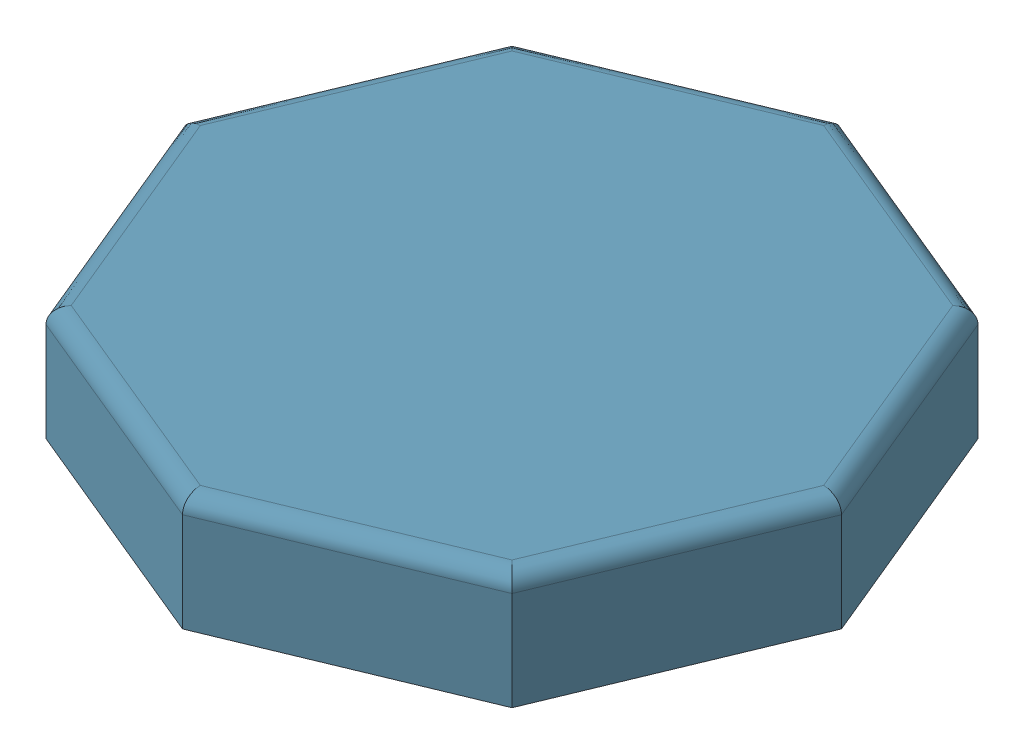
SolidWorks assembly SPYDER_VER_2, configuration Default. Lengths in mm.
Overall size (399.81 90 399.81).
100 component instances, 39 part files, 25 mates.
Components (placement in the parent):
- SP-chassis-1: SP-chassis [Default] at (163.298 278.0074 409.538) x (-1 0 0) z (0 -1 0) size (391.97 371.45 23)
- PIXHWAK PX4 2.8-1: PIXHWAK PX4 2.8 [Default] at (163.298 278.0074 533.5224) size (44.1 12.1 85)
- PIXHAWK_MOUNTS_1-1: PIXHAWK_MOUNTS_1 [Default] at (170.0442 283.0074 574.7577) x (0 0 -1) z (0 -1 0) size (15 50 5)
- PIXHAWK_MOUNTS_1-2: PIXHAWK_MOUNTS_1 [Default] at (169.4157 278.0074 492.2871) x (0 0 1) z (0 1 0) size (15 50 5)
- RasPI-4.iges-1: RasPI-4.iges [Default] at (242.8847 278.0074 515.731) x (-0.92388 0 0.382683) z (-0.382683 0 -0.92388) size (70 53.6 99)
  - Top v2.iges-1: Top v2.iges [Default] at (0 44.6 0) size (70 3 99)
  - Botom Plate v4.iges-1: Botom Plate v4.iges [Default] at origin size (70 3 99)
  - Left side v14.iges-1: Left side v14.iges [Default] at (-32 -3 0) x (0 0 1) z (0 -1 0) size (99 3 50.6)
  - Right side v7.iges-1: Right side v7.iges [Default] at (32 -3 0) x (0 0 -1) z (1 0 0) size (99 50.6 3)
  - Back v9.iges-1: Back v9.iges [Default] at (0 23.5 -49.5) size (70 47.6 3)
  - screw M3 6mm  v1.iges-1: screw M3 6mm  v1.iges [Default] at (-24.5 47.6 19) x (1 0 0) z (0 1 0) size (5 5 9)
  - screw M3 6mm  v1.iges-2: screw M3 6mm  v1.iges [Default] at (-24.5 47.6 -39) x (1 0 0) z (0 1 0) size (5 5 9)
  - screw M3 6mm  v1.iges-3: screw M3 6mm  v1.iges [Default] at (24.5 47.5 -39) x (1 0 0) z (0 1 0) size (5 5 9)
  - screw M3 6mm  v1.iges-4: screw M3 6mm  v1.iges [Default] at (24.5 47.5 19) x (1 0 0) z (0 1 0) size (5 5 9)
  - screw M3 6mm  v1.iges-5: screw M3 6mm  v1.iges [Default] at (16 47.5 6) x (1 0 0) z (0 1 0) size (5 5 9)
  - screw M3 6mm  v1.iges-6: screw M3 6mm  v1.iges [Default] at (16 47.5 -26) x (1 0 0) z (0 1 0) size (5 5 9)
  - screw M3 6mm  v1.iges-7: screw M3 6mm  v1.iges [Default] at (-16 47.5 6) x (1 0 0) z (0 1 0) size (5 5 9)
  - screw M3 6mm  v1.iges-8: screw M3 6mm  v1.iges [Default] at (-16 47.5 -26) x (1 0 0) z (0 1 0) size (5 5 9)
  - screw M3 6mm  v1.iges-9: screw M3 6mm  v1.iges [Default] at (24.5 0 -39) x (1 0 0) z (0 -1 0) size (5 5 9)
  - screw M3 6mm  v1.iges-10: screw M3 6mm  v1.iges [Default] at (24.5 0 19) x (1 0 0) z (0 -1 0) size (5 5 9)
  - screw M3 6mm  v1.iges-11: screw M3 6mm  v1.iges [Default] at (-24.5 0 -39) x (1 0 0) z (0 -1 0) size (5 5 9)
  - screw M3 6mm  v1.iges-12: screw M3 6mm  v1.iges [Default] at (-24.5 0 19) x (1 0 0) z (0 -1 0) size (5 5 9)
  - Front v5.iges-1: Front v5.iges [Default] at (0 23.5 46.5) size (70 47.6 3)
  - TFF-M3x5_DR114 v1.iges-1: TFF-M3x5_DR114 v1.iges [Default] at (-24.5 8 19) x (0 -1 0) z (0 0 1) size (5.03 6.35 5.5)
  - TFF-M3x5_DR114 v1.iges-2: TFF-M3x5_DR114 v1.iges [Default] at (24.5 8 19) x (0 -1 0) z (0 0 1) size (5.03 6.35 5.5)
  - TFF-M3x5_DR114 v1.iges-3: TFF-M3x5_DR114 v1.iges [Default] at (-24.5 8 -39) x (0 -1 0) z (0 0 1) size (5.03 6.35 5.5)
  - TFF-M3x5_DR114 v1.iges-4: TFF-M3x5_DR114 v1.iges [Default] at (24.5 8 -39) x (0 -1 0) z (0 0 1) size (5.03 6.35 5.5)
  - TFF-M3x35_DR114 v1.iges-1: TFF-M3x35_DR114 v1.iges [Default] at (-24.5 44.6 19) x (0 -1 0) z (0 0 1) size (35.03 6.35 5.5)
  - TFF-M3x35_DR114 v1.iges-2: TFF-M3x35_DR114 v1.iges [Default] at (24.5 44.6 19) x (0 -1 0) z (0 0 1) size (35.03 6.35 5.5)
  - TFF-M3x35_DR114 v1.iges-3: TFF-M3x35_DR114 v1.iges [Default] at (-24.5 44.6 -39) x (0 -1 0) z (0 0 1) size (35.03 6.35 5.5)
  - TFF-M3x35_DR114 v1.iges-4: TFF-M3x35_DR114 v1.iges [Default] at (24.5 44.6 -39) x (0 -1 0) z (0 0 1) size (35.03 6.35 5.5)
  - raspberry_pi_3_b_plus v40.f3d v1.iges-1: raspberry_pi_3_b_plus v40.f3d v1.iges [Default] at (0 8 0) x (0 0 1) z (0 1 0) size (85 57.31 10.03)
    - pcb.iges-1: pcb.iges [Default] at origin size (85 56 1.6)
    - te_1-1734248-5.iges-1: te_1-1734248-5.iges [Default] at (-38.8804 0.013 1.58) x (0 -1 0) z (-1 0 0) size (22.4 5.68 5.07)
    - te_1-1734248-5.iges-2: te_1-1734248-5.iges [Default] at (2.6829 -16.6511 1.58) x (0 1 0) z (1 0 0) size (22.4 5.68 5.07)
    - SOP-3_1.6mm.iges-1: SOP-3_1.6mm.iges [Default] at (-40.8905 -10.8155 0) x (-1 0 0) z (0 0 -1) size (1.61 1.56 0.65)
    - SOP-3_1.6mm.iges-2: SOP-3_1.6mm.iges [Default] at (-40.814 -18.4594 0) x (-1 0 0) z (0 0 -1) size (1.61 1.56 0.65)
    - SOP-3_1.6mm.iges-3: SOP-3_1.6mm.iges [Default] at (-16.6511 -13.2136 1.6) x (0 1 0) z (0 0 1) size (1.61 1.56 0.65)
    - SOP-3_1.6mm.iges-4: SOP-3_1.6mm.iges [Default] at (-16.6511 -11.1136 1.6) x (0 1 0) z (0 0 1) size (1.61 1.56 0.65)
    - micro_usb_connector v17.iges-1: micro_usb_connector v17.iges [Default] at (-31.9022 -25.6898 1.6) x (0 -1 0) z (0 0 1) size (5.84 7.77 3.4)
      - shield.iges-1: shield.iges [Default] at origin size (5.84 7.77 3.4)
      - socket_housing.iges-1: socket_housing.iges [Default] at origin size (4.25 6.85 2.15)
      - socket_plate.iges-1: socket_plate.iges [Default] at origin size (3.38 6.8 0.31)
      - terminal.iges-1: terminal.iges [Default] at origin size (3.22 0.35 1.72)
      - terminal.iges-2: terminal.iges [Default] at (0 -1.3 0) size (3.22 0.35 1.72)
      - terminal.iges-3: terminal.iges [Default] at (0 -0.65 0) size (3.22 0.35 1.72)
      - terminal.iges-4: terminal.iges [Default] at (0 0.65 0) size (3.22 0.35 1.72)
      - terminal.iges-5: terminal.iges [Default] at (0 1.3 0) size (3.22 0.35 1.72)
    - sd_card_slot_molex v11.iges-1: sd_card_slot_molex v11.iges [Default] at (-35.5259 0.0195 0) x (0 1 0) z (-1 0 0) size (12 1.5 11.41)
      - base.iges-1: base.iges [Default] at origin size (11.85 1.42 10.4)
      - housing.iges-1: housing.iges [Default] at origin size (12 1.43 11.41)
        - shell.iges-1: shell.iges [Default] at origin size (12 1.43 11.41)
      - leads.iges-1: leads.iges [Default] at origin size (10.97 1.35 10.44)
        - Component12.iges-1: Component12.iges [Default] at origin size (0.75 1.24 7.86)
        - Component12.iges-2: Component12.iges [Default] at (-2.2 0 0) size (0.75 1.24 7.86)
        - Component12.iges-3: Component12.iges [Default] at (-4.4 0 0) size (0.75 1.24 7.86)
        - Component12.iges-4: Component12.iges [Default] at (-6.6 0 0) size (0.75 1.24 7.86)
        - Component12.iges-5: Component12.iges [Default] at (-7.7 0 0) size (0.75 1.24 7.86)
        - Component13.iges-1: Component13.iges [Default] at (-1.1 0 0) size (0.75 1.26 8.16)
        - Component14.iges-1: Component14.iges [Default] at (-3.3 0 0) size (0.75 1.23 7.81)
        - Component14.iges-2: Component14.iges [Default] at (-5.5 0 0) size (0.75 1.23 7.81)
        - Component15.iges-1: Component15.iges [Default] at origin size (1.62 1.27 4.5)
        - Component16.iges-1: Component16.iges [Default] at origin size (1.37 1.25 4.89)
    - Pin Header 20x2 TH Pitch 2.54mm v1.iges-1: Pin Header 20x2 TH Pitch 2.54mm v1.iges [Default] at (-34.0983 24.2639 1.6) size (50.8 5.08 10)
      - pins.iges-1: pins.iges [Default] at origin size (48.9 3.17 10)
      - spacers.iges-1: spacers.iges [Default] at origin size (50.8 5.08 2.54)
        - Component67.iges-1: Component67.iges [Default] at origin size (50.8 5.08 2.54)
    - wifi.iges-1: wifi.iges [Default] at origin size (10.5 13 2)
      - Component73.iges-1: Component73.iges [Default] at origin size (10.5 13 2)
  - NF-A4x10_Noctua_40mm v1.iges-1: NF-A4x10_Noctua_40mm v1.iges [Default] at (-30.9345 44.346 -10.0655) size (43.91 12 43.91)
    - NF-A4x10_Noctua_40mm.iges-1: NF-A4x10_Noctua_40mm.iges [Default] at origin size (43.91 12 43.91)
      - Noctua-NF-A4x10 v1.iges-1: Noctua-NF-A4x10 v1.iges [Default] at (31 -5.2451 0) x (1 0 0) z (0 -1 0) size (43.91 43.91 12)
      - Noctua nf-a8-pwm fan 80x80x25 v2.iges-1: Noctua nf-a8-pwm fan 80x80x25 v2.iges [Default] at (31 -0.546 0) x (1 0 0) z (0 -1 0) size (37.1 37.05 8.8)
- Wheels v8.step-1: Wheels v8.step [Default] at (18.8176 292.8598 408.9276) x (0 0.122984 0.992409) z (0 -0.992409 0.122984) size (100 28 100) (hidden)
- Wheels v8.step-2: Wheels v8.step [Default] at (288.798 292.8598 408.9276) x (0 -1 0) z (0 0 1) size (100 28 100) (hidden)
- Pololu DC Motor 37dx52l mm Mounted on Bracket.IGS-1: Pololu DC Motor 37dx52l mm Mounted on Bracket.IGS [Default] at (87.981 238.4588 404.4605) x (0 -1 0) z (-1 0 0) size (40.3 37.6 81.56)
  - pololu-37D-encoder.IGS-1: pololu-37D-encoder.IGS [Default] at (-61.4335 4.4794 28.093) size (36.81 36.81 81.56) (hidden)
  - motorbracket.IGS-1: motorbracket.IGS [Default] at (-41.1385 -14.3156 28.1855) x (0 0 -1) z (0 1 0) size (50.81 39.19 37.6) (hidden)
  - round head screw_ai_CR-RHMS 0.112-48x0.125x0.125-N.IGS-1: round head screw_ai_CR-RHMS 0.112-48x0.125x0.125-N.IGS [Default] at (-74.8569 12.2294 51.9919) x (0 0 -1) z (0.998811 0.048747 0) size (5.32 5.37 5.37) (hidden)
  - round head screw_ai_CR-RHMS 0.112-48x0.125x0.125-N.IGS-2: round head screw_ai_CR-RHMS 0.112-48x0.125x0.125-N.IGS [Default] at (-61.4335 19.9794 50.2774) x (0 0 -1) z (1 0 0) size (5.32 5.37 5.37) (hidden)
  - round head screw_ai_CR-RHMS 0.112-48x0.125x0.125-N.IGS-3: round head screw_ai_CR-RHMS 0.112-48x0.125x0.125-N.IGS [Default] at (-48.0101 12.2294 50.2774) x (0 0 -1) z (1 0 0) size (5.32 5.37 5.37) (hidden)
  - round head screw_ai_CR-RHMS 0.112-48x0.125x0.125-N.IGS-4: round head screw_ai_CR-RHMS 0.112-48x0.125x0.125-N.IGS [Default] at (-61.4335 -11.0206 51.8674) x (0 0 -1) z (1 0 0) size (5.32 5.37 5.37) (hidden)
  - round head screw_ai_CR-RHMS 0.112-48x0.125x0.125-N.IGS-5: round head screw_ai_CR-RHMS 0.112-48x0.125x0.125-N.IGS [Default] at (-48.0101 -3.2706 51.8674) x (0 0 -1) z (1 0 0) size (5.32 5.37 5.37) (hidden)
  - round head screw_ai_CR-RHMS 0.112-48x0.125x0.125-N.IGS-6: round head screw_ai_CR-RHMS 0.112-48x0.125x0.125-N.IGS [Default] at (-48.0101 12.2294 51.8674) x (0 0 -1) z (1 0 0) size (5.32 5.37 5.37) (hidden)
  - round head screw_ai_CR-RHMS 0.112-48x0.125x0.125-N.IGS-7: round head screw_ai_CR-RHMS 0.112-48x0.125x0.125-N.IGS [Default] at (-61.4335 19.9794 51.8674) x (0 0 -1) z (1 0 0) size (5.32 5.37 5.37) (hidden)
  - round head screw_ai_CR-RHMS 0.125-44x0.125x0.125-N.IGS-1: round head screw_ai_CR-RHMS 0.125-44x0.125x0.125-N.IGS [Default] at (-74.8569 -3.2706 52.096) x (0 0 -1) z (1 0 0) size (5.55 6 6) (hidden)
- pololu_37d_1.IGS-1: pololu_37d_1.IGS [Default] at (219.3373 238.4588 413.6866) x (0 -1 0) z (1 0 0) size (40.3 37.6 81.56)
  - pololu-37D-encoder.IGS-1: pololu-37D-encoder.IGS [Default] at (-61.4335 4.4794 28.093) size (36.81 36.81 81.56) (hidden)
  - motorbracket.IGS-1: motorbracket.IGS [Default] at (-41.1385 -14.3156 28.1855) x (0 0 -1) z (0 1 0) size (50.81 39.19 37.6) (hidden)
  - round head screw_ai_CR-RHMS 0.112-48x0.125x0.125-N.IGS-1: round head screw_ai_CR-RHMS 0.112-48x0.125x0.125-N.IGS [Default] at (-74.8569 12.2294 51.9919) x (0 0 -1) z (0.998811 0.048747 0) size (5.32 5.37 5.37) (hidden)
  - round head screw_ai_CR-RHMS 0.112-48x0.125x0.125-N.IGS-2: round head screw_ai_CR-RHMS 0.112-48x0.125x0.125-N.IGS [Default] at (-61.4335 19.9794 50.2774) x (0 0 -1) z (1 0 0) size (5.32 5.37 5.37) (hidden)
  - round head screw_ai_CR-RHMS 0.112-48x0.125x0.125-N.IGS-3: round head screw_ai_CR-RHMS 0.112-48x0.125x0.125-N.IGS [Default] at (-48.0101 12.2294 50.2774) x (0 0 -1) z (1 0 0) size (5.32 5.37 5.37) (hidden)
  - round head screw_ai_CR-RHMS 0.112-48x0.125x0.125-N.IGS-4: round head screw_ai_CR-RHMS 0.112-48x0.125x0.125-N.IGS [Default] at (-61.4335 -11.0206 51.8674) x (0 0 -1) z (1 0 0) size (5.32 5.37 5.37) (hidden)
  - round head screw_ai_CR-RHMS 0.112-48x0.125x0.125-N.IGS-5: round head screw_ai_CR-RHMS 0.112-48x0.125x0.125-N.IGS [Default] at (-48.0101 -3.2706 51.8674) x (0 0 -1) z (1 0 0) size (5.32 5.37 5.37) (hidden)
  - round head screw_ai_CR-RHMS 0.112-48x0.125x0.125-N.IGS-6: round head screw_ai_CR-RHMS 0.112-48x0.125x0.125-N.IGS [Default] at (-48.0101 12.2294 51.8674) x (0 0 -1) z (1 0 0) size (5.32 5.37 5.37) (hidden)
  - round head screw_ai_CR-RHMS 0.112-48x0.125x0.125-N.IGS-7: round head screw_ai_CR-RHMS 0.112-48x0.125x0.125-N.IGS [Default] at (-61.4335 19.9794 51.8674) x (0 0 -1) z (1 0 0) size (5.32 5.37 5.37) (hidden)
  - round head screw_ai_CR-RHMS 0.125-44x0.125x0.125-N.IGS-1: round head screw_ai_CR-RHMS 0.125-44x0.125x0.125-N.IGS [Default] at (-74.8569 -3.2706 52.096) x (0 0 -1) z (1 0 0) size (5.55 6 6) (hidden)
- ROLLER_COVER-1: ROLLER_COVER [Default] at (161.8956 276.3074 652.3613) x (0 0 -1) z (1 0 0) size (154.63 51 250) (hidden)
- SP-body-2: SP-body [Default] at (162.9618 275.0074 410.3498) x (0 0 1) z (-1 0 0) size (399.81 90 399.81)
- ROLLLER-2: ROLLLER [Default] at (36.8956 273.4841 626.1766) size (250 60 60) (hidden)
Mates (geometry in assembly coordinates):
- Coincident7: coincident: plane of SP-chassis-1 through (163.298 278.0074 409.538) normal (0 1 0); plane of PIXHWAK PX4 2.8-1 through (163.298 278.0074 533.5224) normal (0 -1 0)
- Parallel4: parallel: plane of SP-chassis-1 through (3.298 268.0074 352.038) normal (1 0 0); plane of PIXHWAK PX4 2.8-1 through (141.298 288.0074 575.5224) normal (-1 0 0)
- Coincident16: coincident: plane of SP-chassis-1 through (163.298 278.0074 409.538) normal (0 1 0); plane of PIXHAWK_MOUNTS_1-1 through (170.0442 278.0074 574.7577) normal (0 -1 0)
- Coincident17: coincident: plane of PIXHWAK PX4 2.8-1 through (141.298 288.0074 575.5224) normal (0 0 1); plane of PIXHAWK_MOUNTS_1-1 through (170.0442 278.0074 575.5224) normal (0 0 -1)
- Coincident18: coincident: plane of SP-chassis-1 through (163.298 278.0074 409.538) normal (0 1 0); plane of PIXHAWK_MOUNTS_1-2 through (169.4157 278.0074 492.2871) normal (0 -1 0)
- Coincident20: coincident: plane of PIXHWAK PX4 2.8-1 through (141.298 288.0074 575.5224) normal (-1 0 0); plane of PIXHAWK_MOUNTS_1-2 through (141.298 283.0074 492.2871) normal (1 0 0)
- Coincident21: coincident: plane of PIXHWAK PX4 2.8-1 through (141.298 288.0074 491.5224) normal (0 0 -1); plane of PIXHAWK_MOUNTS_1-2 through (169.4157 283.0074 491.5224) normal (0 0 1)
- Tangent1: tangent: plane of SP-chassis-1 through (163.298 278.0074 409.538) normal (0 1 0); face of RasPI-4.iges-1/Botom Plate v4.iges-1
- Tangent2: tangent: plane of SP-chassis-1 through (231.4409 278.0074 574.0495) normal (-0.382683 0 -0.92388); face of RasPI-4.iges-1/Back v9.iges-1
- Parallel5: parallel: plane of SP-chassis-1 through (38.298 268.0074 352.038) normal (-1 0 0); plane of Wheels v8.step-1 through (33.8176 292.8598 408.9276) normal (1 0 0)
- Parallel6: parallel: plane of Wheels v8.step-1 through (31.8176 292.8598 408.9276) normal (1 0 0); plane of Wheels v8.step-2 through (275.798 292.8598 408.9276) normal (-1 0 0)
- Distance3: distance = 5 mm: plane of Wheels v8.step-2 through (275.798 292.8598 408.9276) normal (-1 0 0); plane of SP-chassis-1 through (270.798 268.0074 352.038) normal (1 0 0)
- Concentric1: concentric: cylinder of Wheels v8.step-1 through (18.8176 292.8598 408.9276) axis (-1 0 0) radius 5.5; cylinder of Wheels v8.step-2 through (288.798 292.8598 408.9276) axis (1 0 0) radius 5.5
- Tangent6: tangent: plane of SP-chassis-1 through (163.298 278.0074 409.538) normal (0 1 0); face of Pololu DC Motor 37dx52l mm Mounted on Bracket.IGS-1/motorbracket.IGS-1
- Tangent10: tangent: plane of SP-chassis-1 through (38.298 268.0074 352.038) normal (-1 0 0); face of Pololu DC Motor 37dx52l mm Mounted on Bracket.IGS-1/motorbracket.IGS-1
- Lock1: lock: unknown of SP-chassis-1; unknown of Pololu DC Motor 37dx52l mm Mounted on Bracket.IGS-1/motorbracket.IGS-1
- Tangent14: tangent: plane of SP-chassis-1 through (163.298 278.0074 409.538) normal (0 1 0); face of pololu_37d_1.IGS-1/motorbracket.IGS-1
- Lock2: lock: unknown of SP-chassis-1; unknown of pololu_37d_1.IGS-1/pololu-37D-encoder.IGS-1
- Coincident22: coincident: plane of SP-chassis-1 through (163.298 275.0074 409.538) normal (0 -1 0); plane of ROLLER_COVER-1 through (286.8956 275.0074 572.5432) normal (0 1 0)
- Parallel7: parallel: plane of PIXHAWK_MOUNTS_1-1 through (170.0442 278.0074 581.5224) normal (0 0 1); plane of ROLLER_COVER-1 through (286.8956 275.0074 589.5432) normal (0 0 -1)
- Coincident30: coincident: plane of SP-chassis-1 through (301.88 275.0074 270.9561) normal (0.92388 0 -0.382683); plane of SP-body-2 through (360.0943 345.0074 411.4978) normal (-0.92388 0 0.382683)
- Coincident31: coincident: plane of SP-chassis-1 through (163.298 275.0074 409.538) normal (0 -1 0); plane of SP-body-2 through (162.9618 275.0074 410.3498) normal (0 -1 0)
- Coincident32: coincident: plane of SP-chassis-1 through (24.7161 275.0074 270.9561) normal (-0.382683 0 -0.92388); plane of SP-body-2 through (164.1098 345.0074 213.2173) normal (0.382683 0 0.92388)
- Coincident34: coincident: plane of ROLLER_COVER-1 through (286.8956 276.3074 652.3613) normal (1 0 0); plane of ROLLLER-2 through (286.8956 273.4841 626.1766) normal (1 0 0)
- Coincident35: coincident: plane of ROLLER_COVER-1 through (286.8956 275.0074 589.5432) normal (0 0 -1); line of SP-body-2 through (112.9618 275.0074 720.1995) axis (0 1 0)
